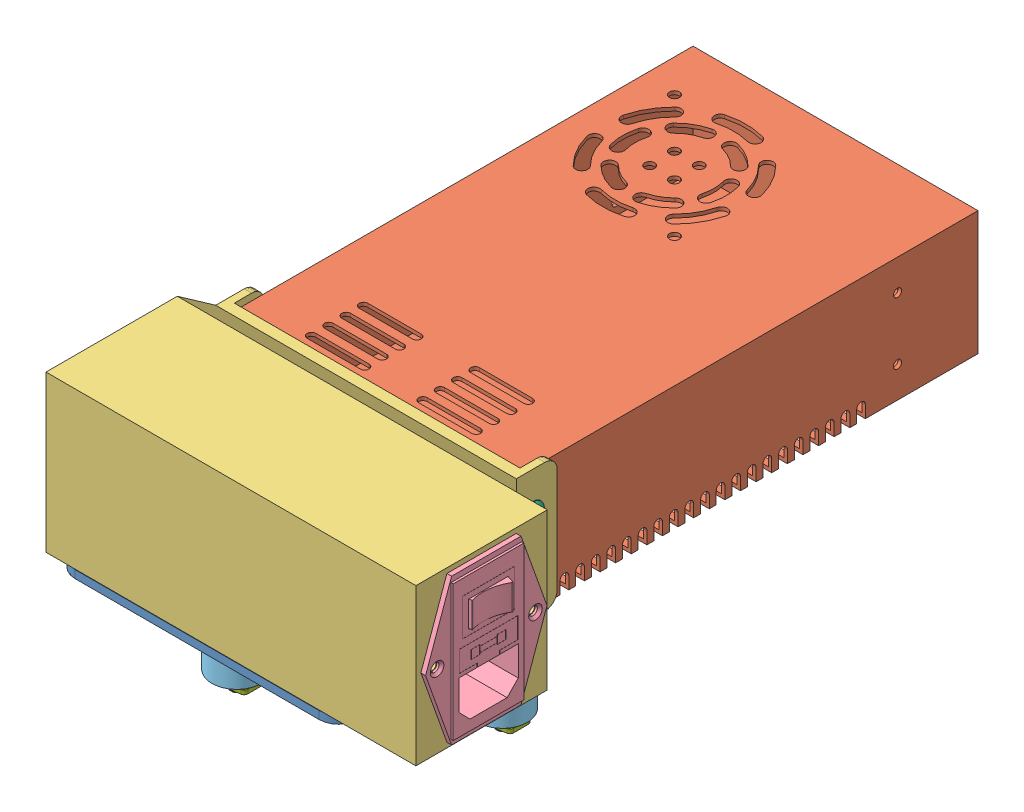
SolidWorks assembly Power Supply ASMB, configuration Default. Lengths in mm.
Overall size (175.67 88.5 258).
17 component instances, 8 part files, 39 mates.
Components (placement in the parent):
- Power Supply Mount-1: Power Supply Mount [Default] at origin size (154.5 3.17 105.18)
- Genssi 24V 14.5A 350W-1: Genssi 24V 14.5A 350W [Default] at (0 3.175 0) x (0 0 -1) z (1 0 0) size (215 50 115)
- Power Supply Cover-1: Power Supply Cover [Default] at (-60.65 28.175 86.5) x (0 -1 0) z (0 0 1) size (63 152.3 85)
- Amazon_Electrical_Fused_Plug-1: Amazon_Electrical_Fused_Plug [Default] at (88.65 35.175 124) x (0 0 1) z (1 0 0) size (49 59 24.75)
- PSU_Standoffs-1: PSU_Standoffs [Default] at (-67.25 -7.5 94.175) x (0.794687 0 -0.607019) z (0 -1 0) size (20 20 15)
- PSU_Standoffs-2: PSU_Standoffs [Default] at (0 -7.5 134.175) x (0.666052 0 -0.745905) z (0 -1 0) size (20 20 15)
- PSU_Standoffs-4: PSU_Standoffs [Default] at (67.25 -7.5 94.175) x (0.489594 0 -0.87195) z (0 -1 0) size (20 20 15)
- M4 Button Head x 6mm Long-1: M4 Button Head x 6mm Long [92095A188] at (-62.85 15.675 75) x (0 0 1) z (-1 0 0) size (7.6 7.6 8.34)
- M4 Button Head x 6mm Long-2: M4 Button Head x 6mm Long [92095A188] at (-62.85 40.675 75) x (0 -0.158553 0.987351) z (-1 0 0) size (7.6 7.6 8.34)
- M4 Button Head x 6mm Long-4: M4 Button Head x 6mm Long [92095A188] at (62.85 15.675 75) x (0 0.994504 0.104701) z (1 0 0) size (7.6 7.6 8.34)
- M4 Button Head x 6mm Long-6: M4 Button Head x 6mm Long [92095A188] at (62.85 40.675 75) x (0 0.999933 0.011545) z (1 0 0) size (7.6 7.6 8.34)
- Tee Nut-1: Tee Nut [Default] at (67.25 -16.8 94.175) x (-1 0 0) z (0 -1 0) size (15 10 3)
- Low Profile Screw M5-1: Low Profile Screw M5 [M5 x 25] at (67.25 -21.825 94.175) x (0 -1 0) z (-0.848342 0 0.529449) size (26.62 9 9)
- Tee Nut-2: Tee Nut [Default] at (-67.25 -16.8 94.175) x (-1 0 0) z (0 -1 0) size (15 10 3)
- Low Profile Screw M5-2: Low Profile Screw M5 [M5 x 25] at (-67.25 -21.825 94.175) x (0 -1 0) z (-0.733364 0 0.679836) size (26.62 9 9)
- Tee Nut-3: Tee Nut [Default] at (0 -16.8 134.175) x (-1 0 0) z (0 -1 0) size (15 10 3)
- Low Profile Screw M5-3: Low Profile Screw M5 [M5 x 25] at (0 -21.825 134.175) x (0 -1 0) z (-0.607966 0 0.793963) size (26.62 9 9)
Mates (geometry in assembly coordinates):
- Concentric1: concentric aligned: cylinder of Power Supply Mount-1 through (-25 3.175 75) axis (0 -1 0) radius 2.1; cylinder of Genssi 24V 14.5A 350W-1 through (-25 3.175 75) axis (0 -1 0) radius 1.65
- Coincident1: coincident anti-aligned: plane of Power Supply Mount-1 through (0 3.175 0) normal (0 1 0); plane of Genssi 24V 14.5A 350W-1 through (0 3.175 0) normal (0 -1 0)
- Concentric2: concentric aligned: cylinder of Power Supply Mount-1 through (25 3.175 75) axis (0 -1 0) radius 2.1; cylinder of Genssi 24V 14.5A 350W-1 through (25 3.175 75) axis (0 -1 0) radius 1.65
- Concentric3: concentric aligned: cylinder of Genssi 24V 14.5A 350W-1 through (-57.5 15.675 75) axis (-1 0 0) radius 1.65; cylinder of Power Supply Cover-1 through (66.5897 15.675 75) axis (-1 0 0) radius 2.1
- Concentric4: concentric aligned: cylinder of Genssi 24V 14.5A 350W-1 through (-57.5 40.675 75) axis (-1 0 0) radius 1.65; cylinder of Power Supply Cover-1 through (66.5897 40.675 75) axis (-1 0 0) radius 2.1
- Distance1: distance = 0.15 mm anti-aligned: plane of Genssi 24V 14.5A 350W-1 through (-57.5 53.175 107.5) normal (-1 0 0); plane of Power Supply Cover-1 through (-57.65 28.175 86.5) normal (1 0 0)
- Coincident3: coincident anti-aligned: plane of Power Supply Cover-1 through (88.65 28.175 86.5) normal (1 0 0); plane of Amazon_Electrical_Fused_Plug-1 through (88.65 35.175 124) normal (-1 0 0)
- Coincident6: coincident: plane of Amazon_Electrical_Fused_Plug-1 through (88.65 35.175 124) normal (0 -1 0); point of assembly
- Coincident7: coincident: plane of Amazon_Electrical_Fused_Plug-1 through (88.65 35.175 124) normal (0 0 1); point of assembly
- Parallel1: parallel aligned: plane of Power Supply Cover-1 through (60.65 66.675 86.5) normal (0 1 0); plane of Amazon_Electrical_Fused_Plug-1 through (90.55 64.675 110) normal (0 1 0)
- Concentric5: concentric anti-aligned: cylinder of Power Supply Mount-1 through (-67.25 3.175 94.175) axis (0 -1 0) radius 2.6; cylinder of PSU_Standoffs-1 through (-67.25 -15 94.175) axis (0 1 0) radius 2.75
- Coincident8: coincident anti-aligned: plane of Power Supply Mount-1 through (0 0 0) normal (0 -1 0); plane of PSU_Standoffs-1 through (-67.25 0 94.175) normal (0 1 0)
- Concentric6: concentric anti-aligned: cylinder of Power Supply Mount-1 through (0 3.175 134.175) axis (0 -1 0) radius 2.6; cylinder of PSU_Standoffs-2 through (0 -15 134.175) axis (0 1 0) radius 2.75
- Coincident9: coincident anti-aligned: plane of Power Supply Mount-1 through (0 0 0) normal (0 -1 0); plane of PSU_Standoffs-2 through (0 0 134.175) normal (0 1 0)
- Concentric7: concentric anti-aligned: cylinder of Power Supply Mount-1 through (67.25 3.175 94.175) axis (0 -1 0) radius 2.6; cylinder of PSU_Standoffs-4 through (67.25 -15 94.175) axis (0 1 0) radius 2.75
- Coincident10: coincident anti-aligned: plane of Power Supply Mount-1 through (0 0 0) normal (0 -1 0); plane of PSU_Standoffs-4 through (67.25 0 94.175) normal (0 1 0)
- Concentric8: concentric anti-aligned: cylinder of Power Supply Cover-1 through (66.5897 15.675 75) axis (-1 0 0) radius 2.1; cylinder of M4 Button Head x 6mm Long-1 through (-54.65 15.675 75) axis (1 0 0) radius 2
- Coincident11: coincident anti-aligned: plane of Power Supply Cover-1 through (-60.65 28.175 86.5) normal (-1 0 0); plane of M4 Button Head x 6mm Long-1 through (-60.65 11.875 75) normal (1 0 0)
- Concentric9: concentric anti-aligned: cylinder of Power Supply Cover-1 through (66.5897 40.675 75) axis (-1 0 0) radius 2.1; cylinder of M4 Button Head x 6mm Long-2 through (-54.65 40.675 75) axis (1 0 0) radius 2
- Coincident12: coincident anti-aligned: plane of Power Supply Cover-1 through (-60.65 28.175 86.5) normal (-1 0 0); plane of M4 Button Head x 6mm Long-2 through (-60.65 36.9231 74.3975) normal (1 0 0)
- Concentric10: concentric aligned: cylinder of Power Supply Cover-1 through (66.5897 15.675 75) axis (-1 0 0) radius 2.1; cylinder of M4 Button Head x 6mm Long-4 through (54.65 15.675 75) axis (-1 0 0) radius 2
- Coincident13: coincident anti-aligned: plane of Power Supply Cover-1 through (60.65 28.175 86.5) normal (1 0 0); plane of M4 Button Head x 6mm Long-4 through (60.65 16.0729 71.2209) normal (-1 0 0)
- Concentric11: concentric aligned: cylinder of Power Supply Cover-1 through (66.5897 40.675 75) axis (-1 0 0) radius 2.1; cylinder of M4 Button Head x 6mm Long-6 through (54.65 40.675 75) axis (-1 0 0) radius 2
- Coincident14: coincident anti-aligned: plane of Power Supply Cover-1 through (60.65 28.175 86.5) normal (1 0 0); plane of M4 Button Head x 6mm Long-6 through (60.65 40.7189 71.2003) normal (-1 0 0)
- Concentric12: concentric aligned: cylinder of Power Supply Mount-1 through (67.25 3.175 94.175) axis (0 -1 0) radius 2.6; cylinder of Low Profile Screw M5-1 through (67.25 3.175 94.175) axis (0 -1 0) radius 2.5
- Coincident15: coincident anti-aligned: plane of Power Supply Mount-1 through (0 3.175 0) normal (0 1 0); plane of Low Profile Screw M5-1 through (69.4533 3.175 97.7053) normal (0 -1 0)
- Concentric13: concentric aligned: cylinder of Tee Nut-1 through (67.25 -19.8 94.175) axis (0 -1 0) radius 2.1; cylinder of Low Profile Screw M5-1 through (67.25 3.175 94.175) axis (0 -1 0) radius 2.5
- Parallel2: parallel aligned: plane of Power Supply Mount-1 through (35 3.175 84.175) normal (0 0 -1); plane of Tee Nut-1 through (70.25 -18.4 89.175) normal (0 0 -1)
- Distance2: distance = 1.8 mm anti-aligned: plane of Tee Nut-1 through (61.25 -16.8 91.175) normal (0 1 0); plane of PSU_Standoffs-4 through (67.25 -15 94.175) normal (0 -1 0)
- Concentric14: concentric aligned: cylinder of Tee Nut-2 through (-67.25 -19.8 94.175) axis (0 -1 0) radius 2.1; cylinder of Low Profile Screw M5-2 through (-67.25 3.175 94.175) axis (0 -1 0) radius 2.5
- Concentric15: concentric aligned: cylinder of Power Supply Mount-1 through (-67.25 3.175 94.175) axis (0 -1 0) radius 2.6; cylinder of Low Profile Screw M5-2 through (-67.25 3.175 94.175) axis (0 -1 0) radius 2.5
- Coincident18: coincident anti-aligned: plane of Power Supply Mount-1 through (0 3.175 0) normal (0 1 0); plane of Low Profile Screw M5-2 through (-64.4209 3.175 97.2268) normal (0 -1 0)
- Parallel3: parallel aligned: plane of Power Supply Mount-1 through (35 3.175 84.175) normal (0 0 -1); plane of Tee Nut-2 through (-64.25 -18.4 89.175) normal (0 0 -1)
- Distance3: distance = 1.8 mm anti-aligned: plane of Tee Nut-2 through (-73.25 -16.8 91.175) normal (0 1 0); plane of PSU_Standoffs-1 through (-67.25 -15 94.175) normal (0 -1 0)
- Concentric16: concentric aligned: cylinder of Tee Nut-3 through (0 -19.8 134.175) axis (0 -1 0) radius 2.1; cylinder of Low Profile Screw M5-3 through (0 3.175 134.175) axis (0 -1 0) radius 2.5
- Parallel4: parallel aligned: plane of Power Supply Mount-1 through (35 3.175 84.175) normal (0 0 -1); plane of Tee Nut-3 through (3 -18.4 129.175) normal (0 0 -1)
- Concentric17: concentric aligned: cylinder of Power Supply Mount-1 through (0 3.175 134.175) axis (0 -1 0) radius 2.6; cylinder of Low Profile Screw M5-3 through (0 3.175 134.175) axis (0 -1 0) radius 2.5
- Coincident19: coincident anti-aligned: plane of Power Supply Mount-1 through (0 3.175 0) normal (0 1 0); plane of Low Profile Screw M5-3 through (3.304 3.175 136.705) normal (0 -1 0)
- Distance4: distance = 1.8 mm anti-aligned: plane of Tee Nut-3 through (-6 -16.8 131.175) normal (0 1 0); plane of PSU_Standoffs-2 through (0 -15 134.175) normal (0 -1 0)
